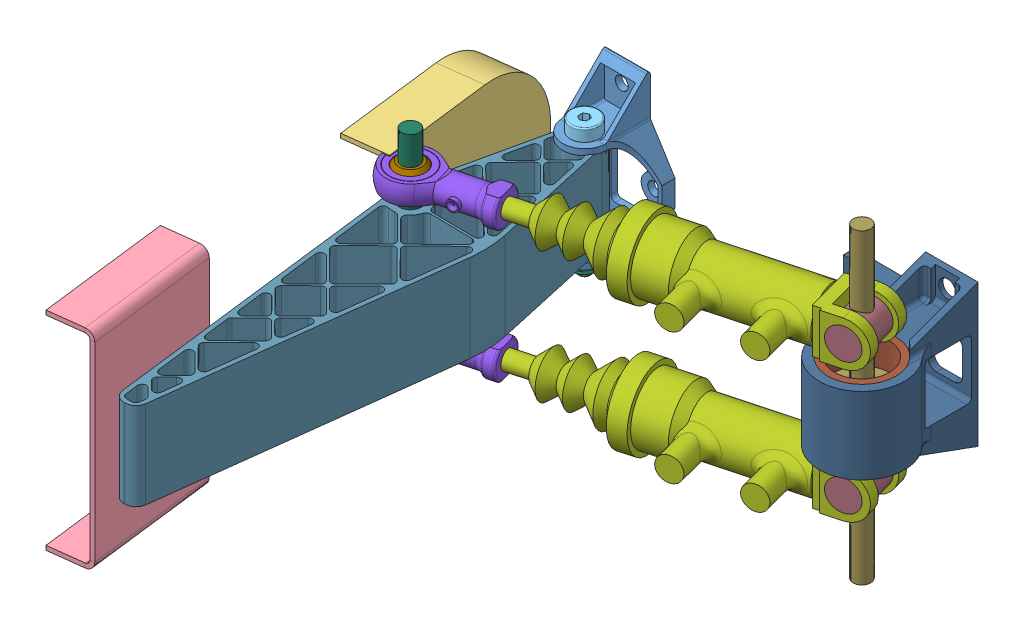
SolidWorks assembly PUTM-F-MS-PB-Brake_Pedal_Assembly, configuration Domyślna. Lengths in mm.
Overall size (219.57 140 242.53).
23 component instances, 15 part files, 29 mates.
Components (placement in the parent):
- PUTM-F-MS-PB-Suport_Brake_Pedal-1: PUTM-F-MS-PB-Suport_Brake_Pedal [Domyślna] at (-59.1985 -43.1594 55.8089) x (0 1 0) z (1 0 0) size (85.17 30 31.29)
- PUTM-F-MS-PB-Bearing-1: PUTM-F-MS-PB-Bearing [Domyślna] at (-59.1985 -53.1046 55.8089) x (0 -1 0) z (0.997379 0 0.07235) size (9.5 15 15)
- PUTM-F-MS-PB-Bearing-2: PUTM-F-MS-PB-Bearing [Domyślna] at (-59.1985 -31.6594 55.8089) x (0 1 0) z (-0.837169 0 -0.546944) size (9.5 15 15)
- PUTM-F-MS-PB-Footcatcher2-1: PUTM-F-MS-PB-Footcatcher2 [Domyślna] at (-87.5974 -41.1046 72.895) x (0 -1 0) z (-0.992546 0 0.121869) size (69 84.5 20)
- PUTM-F-MS-PB-Footcatcher-1: PUTM-F-MS-PB-Footcatcher [Domyślna] at (-69.9837 9.5987 216.3469) x (0 -1 0) z (-0.992546 0 0.121869) size (95 60 20)
- PUTM-FT-ELESA_ISO7379-1: PUTM-FT-ELESA_ISO7379 [8-M6-45] at (-59.1985 -13.6594 55.8089) x (0 1 0) z (0.999709 0 -0.024127) size (61.5 13 13)
- PUTM-FT-FABORY_DIN985-1: PUTM-FT-FABORY_DIN985 [M6 [12348.060.001]] at (-59.1985 -67.1594 55.8089) x (1 0 0) z (0 -1 0) size (11.9 10.35 6.18)
- PUTM-F-MS-PB-AP_Racing_CP7854_Body-1: PUTM-F-MS-PB-AP_Racing_CP7854_Body [Domyślna] at (88.505 -71.6046 77.118) x (0.965591 0 -0.260065) z (0.260065 0 0.965591) size (169.13 33.68 43.84)
- PUTM-F-MS-PB-AP_Racing_CP7854_Body-2: PUTM-F-MS-PB-AP_Racing_CP7854_Body [Domyślna] at (88.505 -11.6046 77.118) x (0.965591 0 -0.260065) z (0.260065 0 0.965591) size (169.13 33.68 43.84)
- PUTM-F-MS-PB-Ball_Joint.stp-1: PUTM-F-MS-PB-Ball_Joint.stp [Domyślna] at (-38.953 -71.6046 111.4465) x (-0.965591 0 0.260065) z (0 1 0) size (48 24 14.86)
  - _Ball joint with female thread GN 648.1-8-M8-N-1.stp-1: _Ball joint with female thread GN 648.1-8-M8-N-1.stp [Domyślna] at origin size (48 24 14.86)
  - _Ball joint with female thread GN 648.1-8-M8-N-2.stp-1: _Ball joint with female thread GN 648.1-8-M8-N-2.stp [Domyślna] at origin size (15.88 15.88 12)
- PUTM-F-MS-PB-Ball_Joint.stp-2: PUTM-F-MS-PB-Ball_Joint.stp [Domyślna] at (-38.953 -11.6046 111.4465) x (-0.965591 0 0.260065) z (0 1 0) size (48 24 14.86)
  - _Ball joint with female thread GN 648.1-8-M8-N-1.stp-1: _Ball joint with female thread GN 648.1-8-M8-N-1.stp [Domyślna] at origin size (48 24 14.86)
  - _Ball joint with female thread GN 648.1-8-M8-N-2.stp-1: _Ball joint with female thread GN 648.1-8-M8-N-2.stp [Domyślna] at origin size (15.88 15.88 12)
- PUTM-F-MS-PB-Brake_Pedal_Suport-1: PUTM-F-MS-PB-Brake_Pedal_Suport [Domyślna] at (88.4217 -41.6046 76.8089) x (0 -1 0) z (-1 0 0) size (65 60.5 64)
- PUTM-F-MS-PB-Balance_bar_Assembly-1: PUTM-F-MS-PB-Balance_bar_Assembly [Domyślna] at (71.7911 -54.4289 63.1427) x (0 -1 0) z (1 0 0) size (140 31 31)
  - PUTM-F-MS-PB-Balance_bar_1-1: PUTM-F-MS-PB-Balance_bar_1 [Domyślna] at (-30.3244 -13.6662 16.6307) size (35 31 31)
  - PUTM-F-MS-PB-Balance_bar_2-1: PUTM-F-MS-PB-Balance_bar_2 [Domyślna] at (57.1756 -13.6662 16.6307) x (0 -1 0) z (1 0 0) size (25 25 140)
- PUTM-F-MS-PB-Clevis_Pivot2-1: PUTM-F-MS-PB-Clevis_Pivot2 [Domyślna] at (85.301 -11.6046 65.2218) x (0.260065 0 0.965591) z (-0.965591 0 0.260065) size (24 16 16)
- PUTM-F-MS-PB-Clevis_Pivot2-2: PUTM-F-MS-PB-Clevis_Pivot2 [Domyślna] at (85.301 -71.6046 65.2218) x (0.260065 0 0.965591) z (-0.965591 0 0.260065) size (24 16 16)
- PUTM-F-MS-PB-Brake_Pedal-1: PUTM-F-MS-PB-Brake_Pedal [Domyślna] at (-65.7143 -41.6046 55.8089) x (0 -1 0) z (-1 0 0) size (40 218 44.19)
- PUTM-F-MS-PB-Pump_Pivot-2: PUTM-F-MS-PB-Pump_Pivot [Domyślna] at (-73.7143 -42.6046 120.8089) x (0 -1 0) z (0.255094 0 -0.966916) size (98 10 10)
Mates (geometry in assembly coordinates):
- Koncentryczne3: concentric aligned: cylinder of PUTM-F-MS-PB-Suport_Brake_Pedal-1 through (-59.1985 -19.1594 55.8089) axis (0 -1 0) radius 4; cylinder of PUTM-F-MS-PB-Bearing-2 through (-59.1985 -23.1594 55.8089) axis (0 -1 0) radius 4
- Odległość1: distance = 0.25 mm anti-aligned: plane of PUTM-F-MS-PB-Bearing-2 through (-59.1985 -22.1594 55.8089) normal (0 1 0); plane of PUTM-F-MS-PB-Suport_Brake_Pedal-1 through (-69.1985 -21.9094 65.8089) normal (0 -1 0)
- Koncentryczne4: concentric anti-aligned: cylinder of PUTM-F-MS-PB-Bearing-1 through (-59.1985 -61.6046 55.8089) axis (0 1 0) radius 4; cylinder of PUTM-FT-ELESA_ISO7379-1 through (-59.1985 -13.6594 55.8089) axis (0 -1 0) radius 4
- Wspólnie14: coincident anti-aligned: plane of PUTM-F-MS-PB-Suport_Brake_Pedal-1 through (-59.1985 -19.1594 55.8089) normal (0 1 0); plane of PUTM-FT-ELESA_ISO7379-1 through (-59.0417 -19.1594 62.307) normal (0 -1 0)
- Koncentryczne5: concentric anti-aligned: cylinder of PUTM-FT-ELESA_ISO7379-1 through (-59.1985 -13.6594 55.8089) axis (0 -1 0) radius 3; cylinder of PUTM-FT-FABORY_DIN985-1 through (-59.1985 -71.1594 55.8089) axis (0 1 0) radius 3
- Wspólnie15: coincident anti-aligned: plane of PUTM-F-MS-PB-Suport_Brake_Pedal-1 through (-59.1985 -67.1594 55.8089) normal (0 -1 0); plane of PUTM-FT-FABORY_DIN985-1 through (-59.1985 -67.1594 55.8089) normal (0 1 0)
- Równolegle3: parallel aligned: cylinder of PUTM-F-MS-PB-AP_Racing_CP7854_Body-1 through (85.6263 -71.6046 77.8933) axis (0.965591 0 -0.260065) radius 11.46; cylinder of PUTM-F-MS-PB-AP_Racing_CP7854_Body-2 through (85.6263 -11.6046 77.8933) axis (0.965591 0 -0.260065) radius 11.46
- Równolegle4: parallel aligned: cylinder of PUTM-F-MS-PB-AP_Racing_CP7854_Body-1 through (-65.024 -71.6046 118.4683) axis (0.965591 0 -0.260065) radius 4; cylinder of PUTM-F-MS-PB-AP_Racing_CP7854_Body-2 through (-65.024 -11.6046 118.4683) axis (0.965591 0 -0.260065) radius 4
- Odległość7: distance = 60 mm: cylinder of PUTM-F-MS-PB-AP_Racing_CP7854_Body-1 through (-65.024 -71.6046 118.4683) axis (0.965591 0 -0.260065) radius 4; cylinder of PUTM-F-MS-PB-AP_Racing_CP7854_Body-2 through (-65.024 -11.6046 118.4683) axis (0.965591 0 -0.260065) radius 4
- Koncentryczne17: concentric aligned: cylinder of PUTM-F-MS-PB-Brake_Pedal_Suport-1 through (88.4217 -59.1046 76.8089) axis (0 1 0) radius 15.5; cylinder of PUTM-F-MS-PB-Balance_bar_Assembly-1/PUTM-F-MS-PB-Balance_bar_1-1 through (88.4217 -59.1046 76.8089) axis (0 1 0) radius 15.5
- Wspólnie21: coincident aligned: plane of PUTM-F-MS-PB-Brake_Pedal_Suport-1 through (88.4217 -24.1046 76.8089) normal (0 1 0); plane of PUTM-F-MS-PB-Balance_bar_Assembly-1/PUTM-F-MS-PB-Balance_bar_1-1 through (88.4217 -24.1046 76.8089) normal (0 1 0)
- Koncentryczne18: concentric anti-aligned: cylinder of PUTM-F-MS-PB-AP_Racing_CP7854_Body-2 through (84.0713 -11.6046 60.6563) axis (0.260065 0 0.965591) radius 7; cylinder of PUTM-F-MS-PB-Clevis_Pivot2-1 through (85.301 -11.6046 65.2218) axis (-0.260065 0 -0.965591) radius 8
- Koncentryczne21: concentric anti-aligned: cylinder of PUTM-F-MS-PB-AP_Racing_CP7854_Body-1 through (84.0713 -71.6046 60.6563) axis (0.260065 0 0.965591) radius 7; cylinder of PUTM-F-MS-PB-Clevis_Pivot2-2 through (85.301 -71.6046 65.2218) axis (-0.260065 0 -0.965591) radius 8
- Koncentryczne22: concentric aligned: cylinder of PUTM-F-MS-PB-Balance_bar_Assembly-1/PUTM-F-MS-PB-Balance_bar_2-1 through (88.4217 -111.6046 76.8089) axis (0 -1 0) radius 4; cylinder of PUTM-F-MS-PB-Clevis_Pivot2-2 through (88.4217 -63.6036 76.8089) axis (0 -1 0) radius 4
- Równolegle8: parallel aligned: cylinder of PUTM-F-MS-PB-Balance_bar_Assembly-1/PUTM-F-MS-PB-Balance_bar_2-1 through (88.4217 -111.6046 76.8089) axis (0 -1 0) radius 4; cylinder of PUTM-F-MS-PB-Clevis_Pivot2-1 through (88.4217 -3.6036 76.8089) axis (0 -1 0) radius 4
- Wspólnie23: coincident aligned: plane of PUTM-F-MS-PB-AP_Racing_CP7854_Body-2 through (101.324 -28.6529 85.7615) normal (0.260065 0 0.965591); plane of PUTM-F-MS-PB-Clevis_Pivot2-1 through (91.5425 -11.6046 88.396) normal (0.260065 0 0.965591)
- Równolegle9: parallel aligned: cylinder of PUTM-F-MS-PB-Balance_bar_Assembly-1/PUTM-F-MS-PB-Balance_bar_2-1 through (88.4217 -111.6046 76.8089) axis (0 -1 0) radius 4; cylinder of PUTM-F-MS-PB-Clevis_Pivot2-1 through (88.4217 -3.6036 76.8089) axis (0 -1 0) radius 4
- Wspólnie24: coincident aligned: plane of PUTM-F-MS-PB-AP_Racing_CP7854_Body-1 through (101.324 -88.6529 85.7615) normal (0.260065 0 0.965591); plane of PUTM-F-MS-PB-Clevis_Pivot2-2 through (91.5425 -71.6046 88.396) normal (0.260065 0 0.965591)
- Koncentryczne23: concentric anti-aligned: cylinder of PUTM-F-MS-PB-Bearing-2 through (-59.1985 -23.1594 55.8089) axis (0 -1 0) radius 5; cylinder of PUTM-F-MS-PB-Brake_Pedal-1 through (-59.1985 -61.6046 55.8089) axis (0 1 0) radius 5
- Koncentryczne24: concentric aligned: cylinder of PUTM-F-MS-PB-Bearing-1 through (-59.1985 -61.6046 55.8089) axis (0 1 0) radius 5; cylinder of PUTM-F-MS-PB-Brake_Pedal-1 through (-59.1985 -61.6046 55.8089) axis (0 1 0) radius 5
- Wspólnie27: coincident anti-aligned: plane of PUTM-F-MS-PB-Bearing-1 through (-59.1985 -61.6046 55.8089) normal (0 1 0); plane of PUTM-F-MS-PB-Brake_Pedal-1 through (-65.7143 -61.6046 55.8089) normal (0 -1 0)
- Wspólnie29: coincident anti-aligned: plane of PUTM-F-MS-PB-Footcatcher-1 through (-69.9837 9.5987 216.3469) normal (0.992546 0 -0.121869); plane of PUTM-F-MS-PB-Brake_Pedal-1 through (-89.3391 -61.6046 58.7096) normal (-0.992546 0 0.121869)
- Wspólnie30: coincident anti-aligned: plane of PUTM-F-MS-PB-Footcatcher2-1 through (-87.5974 -41.1046 72.895) normal (0.992546 0 -0.121869); plane of PUTM-F-MS-PB-Brake_Pedal-1 through (-89.3391 -61.6046 58.7096) normal (-0.992546 0 0.121869)
- Wspólnie31: coincident aligned: line of PUTM-F-MS-PB-Footcatcher2-1 through (-81.5039 -6.6046 122.5223) axis (0 -1 0); line of PUTM-F-MS-PB-Brake_Pedal-1 through (-81.5039 -21.6046 122.5223) axis (0 -1 0)
- Odległość12: distance = 15 mm: line of PUTM-F-MS-PB-Brake_Pedal-1 through (-81.3381 -21.6046 119.1241) axis (0.217952 0 -0.97596); line of PUTM-F-MS-PB-Footcatcher2-1 through (-87.5974 -6.6046 72.895) axis (0.121869 0 0.992546)
- Wspólnie38: coincident aligned: plane of PUTM-F-MS-PB-Suport_Brake_Pedal-1 through (-59.1985 -19.1594 35.8089) normal (0 0 -1); plane of PUTM-F-MS-PB-Brake_Pedal_Suport-1 through (58.9217 -59.1046 35.8089) normal (0 0 -1)
- Koncentryczne30: concentric aligned: cylinder of PUTM-F-MS-PB-Brake_Pedal-1 through (-73.7143 -61.6046 120.8089) axis (0 1 0) radius 5; cylinder of PUTM-F-MS-PB-Pump_Pivot-2 through (-73.7143 -17.6046 120.8089) axis (0 1 0) radius 5
- Odległość14: distance = 2.5 mm aligned: plane of PUTM-F-MS-PB-Brake_Pedal_Suport-1 through (88.4217 -24.1046 76.8089) normal (0 1 0); plane of PUTM-F-MS-PB-Brake_Pedal-1 through (-65.7143 -21.6046 55.8089) normal (0 1 0)
- Kąt1: planar angle = 0.122173 rad aligned: plane of PUTM-F-MS-PB-Brake_Pedal-1 through (-89.3391 -61.6046 58.7096) normal (-0.992546 0 0.121869); plane of PUTM-F-MS-PB-Suport_Brake_Pedal-1 through (-69.1985 -19.1594 55.8089) normal (-1 0 0)
